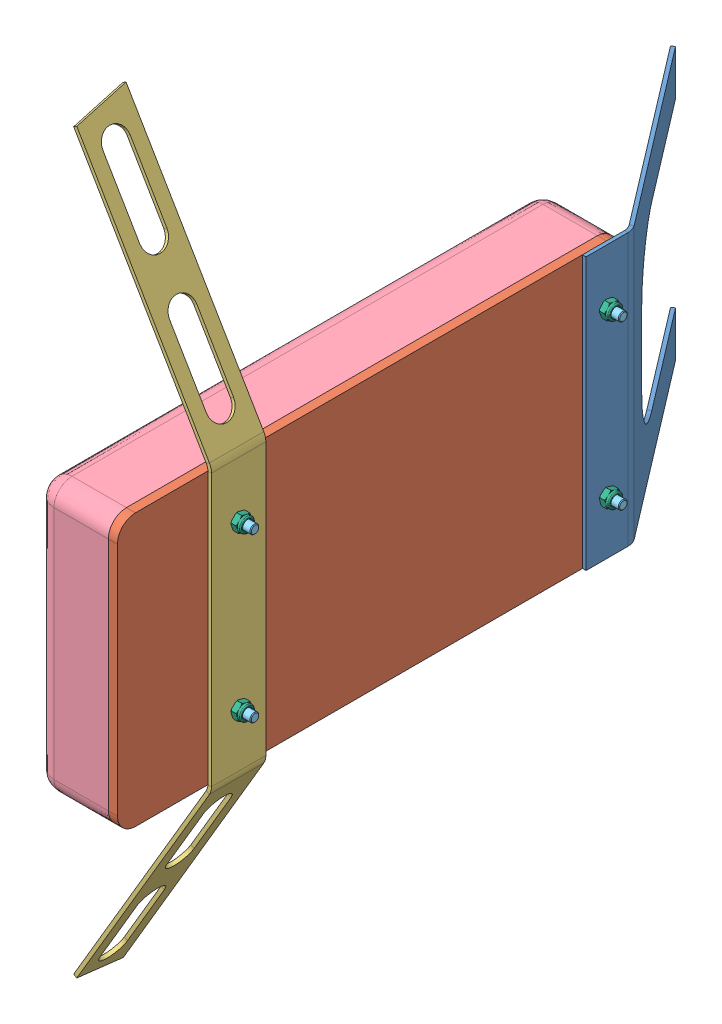
SolidWorks assembly PUTM-F-HR-Assembly1, configuration Domyślna. Lengths in mm.
Overall size (89.43 419.32 382.1).
12 component instances, 6 part files, 25 mates.
Components (placement in the parent):
- PUTM-F-HR-Lower-Mounting-1: PUTM-F-HR-Lower-Mounting [Domyślna] at (-1087.1495 -136.7912 -472.1205) x (1 0 0) z (0 1 0) size (77.51 125.32 150)
- PUTM-F-HR-Plate-1: PUTM-F-HR-Plate [Domyślna] at (-1086.1495 -61.7912 -470.3481) size (5 150 280)
- PUTM-F-HR-Upper-Mounting-1: PUTM-F-HR-Upper-Mounting [Domyślna] at (-122.6495 -264.3718 352.1619) size (80.43 419.32 30.01)
- PUTM-F-HR-Padding-1: PUTM-F-HR-Padding [Domyślna] at (-1086.1495 -61.7912 -470.3481) size (40 150 280)
- PUTM-FT-FABORY_DIN7984-3: PUTM-FT-FABORY_DIN7984 [M5x16 [07090.050.016]] at (-57.0495 -106.7912 367.1619) x (-1 0 0) z (0 0.692617 0.721306) size (19.5 8.5 8.5)
- PUTM-FT-FABORY_DIN7984-4: PUTM-FT-FABORY_DIN7984 [M5x16 [07090.050.016]] at (-57.0495 -16.7912 367.1619) x (-1 0 0) z (0 0.711245 0.702944) size (19.5 8.5 8.5)
- PUTM-FT-FABORY_DIN7984-5: PUTM-FT-FABORY_DIN7984 [M5x16 [07090.050.016]] at (-57.0495 -106.7912 163.7719) x (-1 0 0) z (0 0.541029 0.841004) size (19.5 8.5 8.5)
- PUTM-FT-FABORY_DIN7984-6: PUTM-FT-FABORY_DIN7984 [M5x16 [07090.050.016]] at (-57.0495 -16.7912 163.7719) x (-1 0 0) z (0 0.999977 -0.006855) size (19.5 8.5 8.5)
- PUTM-FT-FABORY_DIN985-1: PUTM-FT-FABORY_DIN985 [M5 [12348.050.001]] at (-46.5495 -16.7912 163.7719) x (0 -0.936013 -0.351966) z (1 0 0) size (9.51 8.27 5.13)
- PUTM-FT-FABORY_DIN985-2: PUTM-FT-FABORY_DIN985 [M5 [12348.050.001]] at (-46.5495 -106.7912 163.7719) x (0 -0.978858 -0.204539) z (1 0 0) size (9.51 8.27 5.13)
- PUTM-FT-FABORY_DIN985-3: PUTM-FT-FABORY_DIN985 [M5 [12348.050.001]] at (-46.5495 -106.7912 367.1619) x (0 0.705918 -0.708293) z (1 0 0) size (9.51 8.27 5.13)
- PUTM-FT-FABORY_DIN985-4: PUTM-FT-FABORY_DIN985 [M5 [12348.050.001]] at (-46.5495 -16.7912 367.1619) x (0 0.955535 0.294877) z (1 0 0) size (9.51 8.27 5.13)
Mates (geometry in assembly coordinates):
- Wspólnie1: coincident anti-aligned: plane of PUTM-F-HR-Lower-Mounting-1 through (-48.5495 13.2088 175.3795) normal (-1 0 0); plane of PUTM-F-HR-Plate-1 through (-48.5495 3.2088 162.1619) normal (1 0 0)
- Koncentryczne1: concentric anti-aligned: cylinder of PUTM-F-HR-Lower-Mounting-1 through (-46.5495 -106.7912 163.7719) axis (1 0 0) radius 2.75; cylinder of PUTM-F-HR-Plate-1 through (-53.5495 -106.7912 163.7719) axis (-1 0 0) radius 2.75
- Koncentryczne2: concentric anti-aligned: cylinder of PUTM-F-HR-Lower-Mounting-1 through (-46.5495 -16.7912 163.7719) axis (1 0 0) radius 2.75; cylinder of PUTM-F-HR-Plate-1 through (-53.5495 -16.7912 163.7719) axis (-1 0 0) radius 2.75
- Wspólnie2: coincident anti-aligned: plane of PUTM-F-HR-Plate-1 through (-48.5495 3.2088 162.1619) normal (1 0 0); plane of PUTM-F-HR-Upper-Mounting-1 through (-48.5495 14.9382 382.1619) normal (-1 0 0)
- Koncentryczne3: concentric anti-aligned: cylinder of PUTM-F-HR-Plate-1 through (-53.5495 -106.7912 367.1619) axis (-1 0 0) radius 2.75; cylinder of PUTM-F-HR-Upper-Mounting-1 through (-46.5495 -106.7912 367.1619) axis (1 0 0) radius 2.75
- Równolegle2: parallel anti-aligned: line of PUTM-F-HR-Plate-1 through (-48.5495 13.2088 162.1619) axis (0 0 1); line of PUTM-F-HR-Upper-Mounting-1 through (-48.5495 13.2076 382.1619) axis (0 0 -1)
- Wspólnie4: coincident anti-aligned: plane of PUTM-F-HR-Plate-1 through (-53.5495 3.2088 162.1619) normal (-1 0 0); plane of PUTM-F-HR-Padding-1 through (-53.5495 3.2088 162.1619) normal (1 0 0)
- Wspólnie5: coincident anti-aligned: circle of PUTM-F-HR-Plate-1; circle of PUTM-F-HR-Padding-1
- Wspólnie6: coincident anti-aligned: circle of PUTM-F-HR-Plate-1; circle of PUTM-F-HR-Padding-1
- Koncentryczne6: concentric aligned: cylinder of PUTM-F-HR-Plate-1 through (-53.5495 -106.7912 367.1619) axis (-1 0 0) radius 2.75; cylinder of PUTM-FT-FABORY_DIN7984-3 through (-57.0495 -106.7912 367.1619) axis (-1 0 0) radius 2.45
- Wspólnie7: coincident anti-aligned: plane of PUTM-F-HR-Plate-1 through (-53.5495 3.2088 162.1619) normal (-1 0 0); plane of PUTM-FT-FABORY_DIN7984-3 through (-53.5495 -109.8568 370.1055) normal (1 0 0)
- Koncentryczne7: concentric aligned: cylinder of PUTM-F-HR-Plate-1 through (-53.5495 -16.7912 367.1619) axis (-1 0 0) radius 2.75; cylinder of PUTM-FT-FABORY_DIN7984-4 through (-57.0495 -16.7912 367.1619) axis (-1 0 0) radius 2.45
- Wspólnie8: coincident anti-aligned: plane of PUTM-F-HR-Plate-1 through (-53.5495 3.2088 162.1619) normal (-1 0 0); plane of PUTM-FT-FABORY_DIN7984-4 through (-53.5495 -19.7787 370.1847) normal (1 0 0)
- Koncentryczne8: concentric aligned: cylinder of PUTM-F-HR-Plate-1 through (-53.5495 -106.7912 163.7719) axis (-1 0 0) radius 2.75; cylinder of PUTM-FT-FABORY_DIN7984-5 through (-57.0495 -106.7912 163.7719) axis (-1 0 0) radius 2.45
- Wspólnie9: coincident anti-aligned: plane of PUTM-F-HR-Plate-1 through (-53.5495 3.2088 162.1619) normal (-1 0 0); plane of PUTM-FT-FABORY_DIN7984-5 through (-53.5495 -110.3655 166.0713) normal (1 0 0)
- Koncentryczne9: concentric aligned: cylinder of PUTM-F-HR-Plate-1 through (-53.5495 -16.7912 163.7719) axis (-1 0 0) radius 2.75; cylinder of PUTM-FT-FABORY_DIN7984-6 through (-57.0495 -16.7912 163.7719) axis (-1 0 0) radius 2.45
- Wspólnie10: coincident anti-aligned: plane of PUTM-F-HR-Plate-1 through (-53.5495 3.2088 162.1619) normal (-1 0 0); plane of PUTM-FT-FABORY_DIN7984-6 through (-53.5495 -16.7621 168.0218) normal (1 0 0)
- Koncentryczne10: concentric aligned: cylinder of PUTM-FT-FABORY_DIN7984-3 through (-57.0495 -106.7912 367.1619) axis (-1 0 0) radius 2.45; cylinder of PUTM-FT-FABORY_DIN985-3 through (-43.3495 -106.7912 367.1619) axis (-1 0 0) radius 2.5
- Wspólnie11: coincident anti-aligned: plane of PUTM-F-HR-Upper-Mounting-1 through (-46.5495 14.9382 382.1619) normal (1 0 0); plane of PUTM-FT-FABORY_DIN985-3 through (-46.5495 -106.7912 367.1619) normal (-1 0 0)
- Koncentryczne11: concentric aligned: cylinder of PUTM-FT-FABORY_DIN7984-4 through (-57.0495 -16.7912 367.1619) axis (-1 0 0) radius 2.45; cylinder of PUTM-FT-FABORY_DIN985-4 through (-43.3495 -16.7912 367.1619) axis (-1 0 0) radius 2.5
- Wspólnie12: coincident anti-aligned: plane of PUTM-F-HR-Upper-Mounting-1 through (-46.5495 14.9382 382.1619) normal (1 0 0); plane of PUTM-FT-FABORY_DIN985-4 through (-46.5495 -16.7912 367.1619) normal (-1 0 0)
- Koncentryczne12: concentric aligned: cylinder of PUTM-FT-FABORY_DIN7984-6 through (-57.0495 -16.7912 163.7719) axis (-1 0 0) radius 2.45; cylinder of PUTM-FT-FABORY_DIN985-1 through (-43.3495 -16.7912 163.7719) axis (-1 0 0) radius 2.5
- Wspólnie13: coincident anti-aligned: plane of PUTM-F-HR-Lower-Mounting-1 through (-46.5495 13.2088 175.3795) normal (1 0 0); plane of PUTM-FT-FABORY_DIN985-1 through (-46.5495 -16.7912 163.7719) normal (-1 0 0)
- Koncentryczne13: concentric aligned: cylinder of PUTM-FT-FABORY_DIN7984-5 through (-57.0495 -106.7912 163.7719) axis (-1 0 0) radius 2.45; cylinder of PUTM-FT-FABORY_DIN985-2 through (-43.3495 -106.7912 163.7719) axis (-1 0 0) radius 2.5
- Wspólnie14: coincident anti-aligned: plane of PUTM-F-HR-Lower-Mounting-1 through (-46.5495 13.2088 175.3795) normal (1 0 0); plane of PUTM-FT-FABORY_DIN985-2 through (-46.5495 -106.7912 163.7719) normal (-1 0 0)
